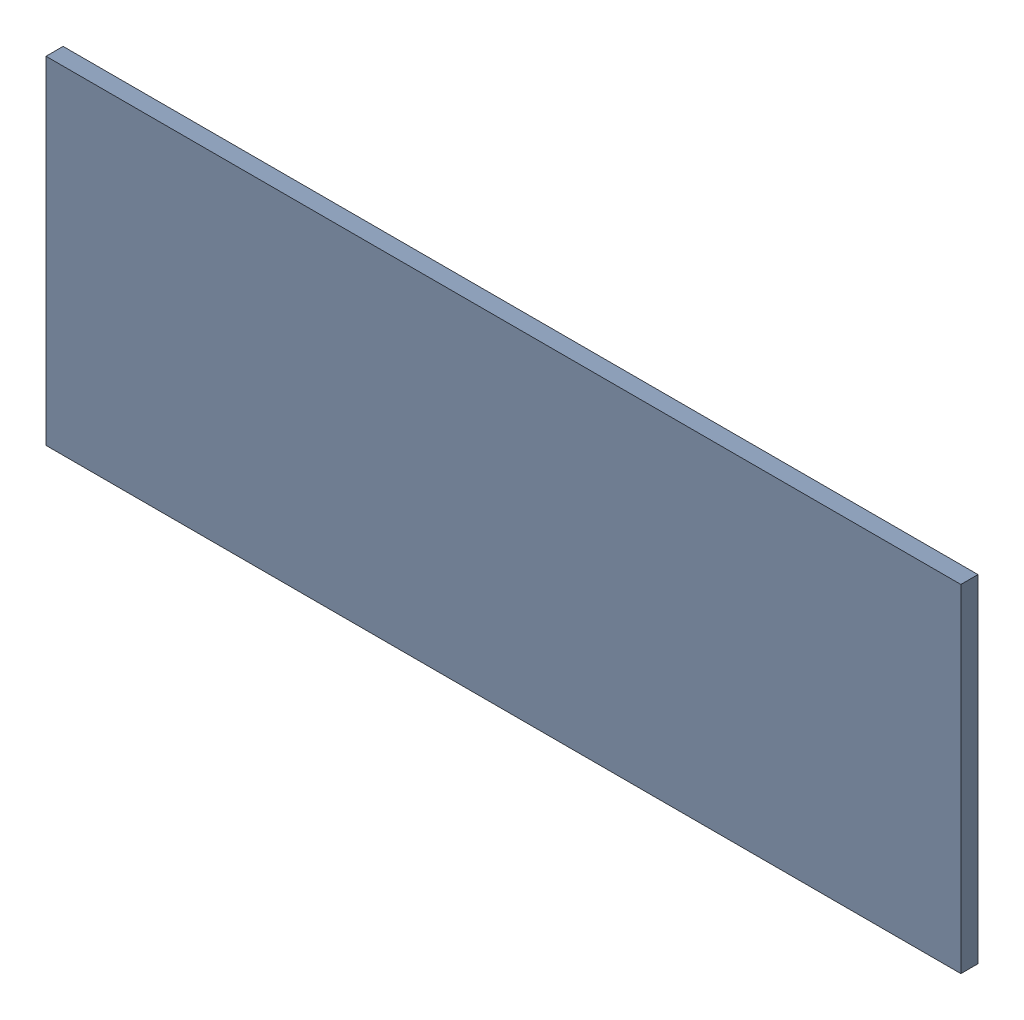
SolidWorks assembly Pad RAK4600-32(29.2mm,25mm) on Top Layer, configuration Predeterminado. Lengths in mm.
Overall size (1.9 0.7 0.04).
2 component instances, 1 part files, 0 mates.
Components (placement in the parent):
- Pad RAK4600-32(29.2mm,25mm) on Top Layer-1-1: Pad RAK4600-32(29.2mm,25mm) on Top Layer-1 [Predeterminado] at (-68.317 -44.187 -0.0457) size (1.9 0.7 0.04)
  - Pad RAK4600-32(29.2mm,25mm) on Top Layer-Part-1-1: Pad RAK4600-32(29.2mm,25mm) on Top Layer-Part-1 [Predeterminado] at origin size (1.9 0.7 0.04)
